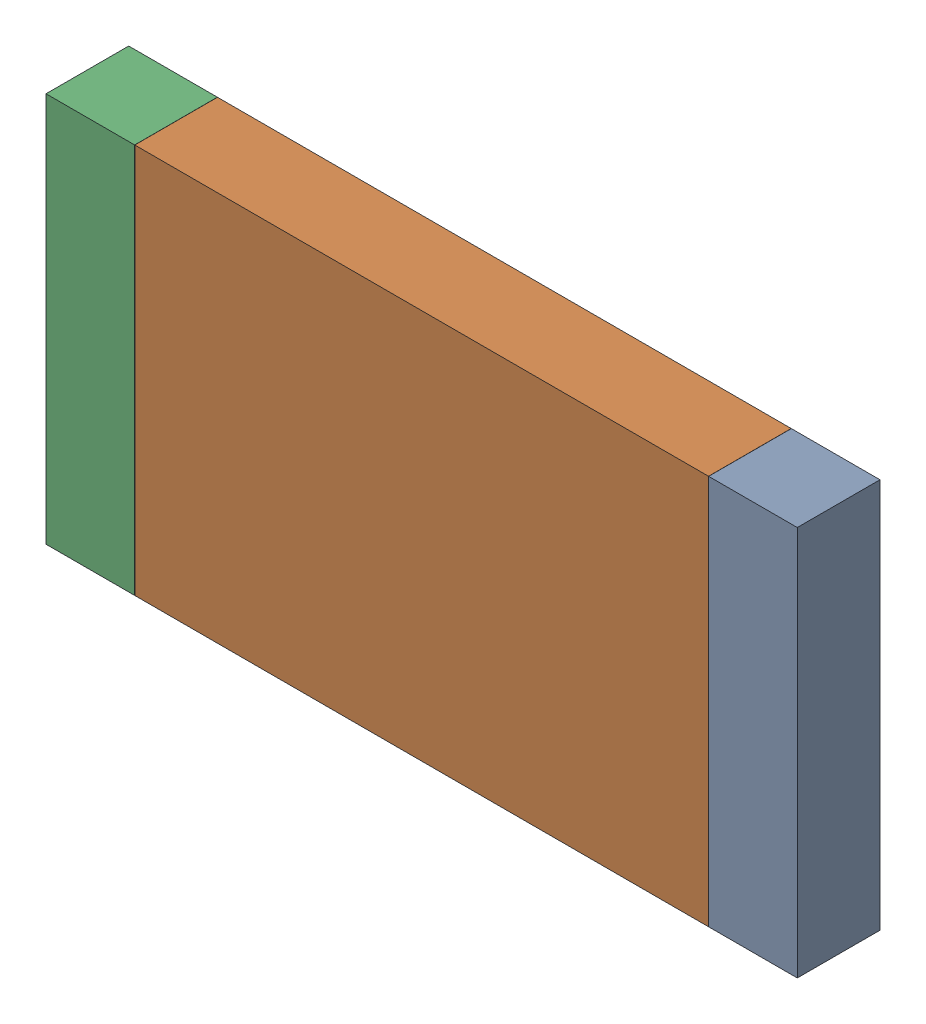
SolidWorks assembly R10, configuration Default. Lengths in mm.
Overall size (6.45 3.35 0.71).
6 component instances, 2 part files, 0 mates.
Components (placement in the parent):
- 6638401968-1: 6638401968 [Default] at (17.957 35.814 0) size (0.76 3.35 0.71)
  - Extruded_10-1: Extruded_10 [Default] at origin size (0.76 3.35 0.71)
- 6638401808-1: 6638401808 [Default] at (15.113 35.814 0) size (4.92 3.35 0.71)
  - Extruded_11-1: Extruded_11 [Default] at origin size (4.92 3.35 0.71)
- 6638401968-2: 6638401968 [Default] at (12.269 35.814 0) size (0.76 3.35 0.71)
  - Extruded_10-1: Extruded_10 [Default] at origin size (0.76 3.35 0.71)
